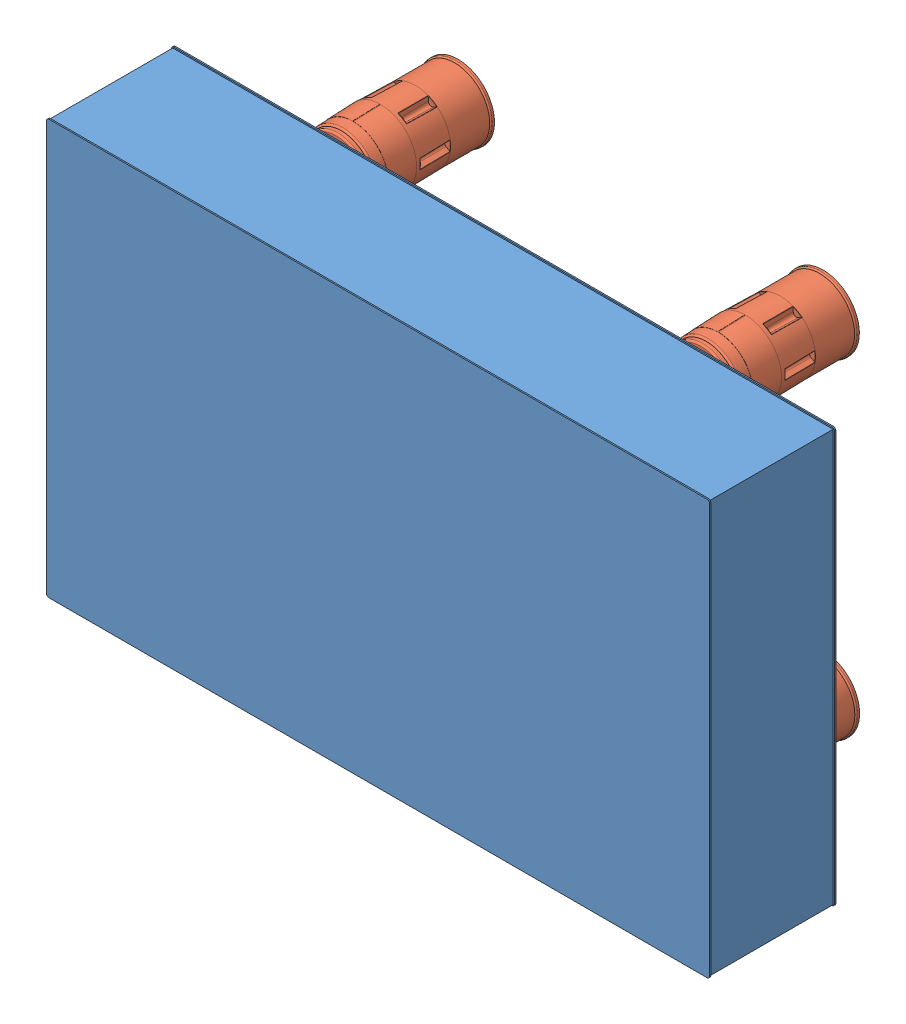
SolidWorks assembly table_with_legs_large, configuration Default. Lengths in mm.
Overall size (2400 1500 950.88).
5 component instances, 2 part files, 12 mates.
Components (placement in the parent):
- M-RS-58-18-1: M-RS-58-18 [Default] at (-679.8721 921.2576 1141.4726) x (1 0 0) z (0 -1 0) size (2400 457 1500)
- S-2000-119.5-2: S-2000-119.5 [-000] at (-19.6071 1517.7497 633.0884) size (263.3 283.03 493.88)
- S-2000-119.5-3: S-2000-119.5 [-000] at (-1340.137 1517.7497 633.0884) size (263.3 283.03 493.88)
- S-2000-119.5-4: S-2000-119.5 [-000] at (-1340.137 324.7654 633.0884) size (263.3 283.03 493.88)
- S-2000-119.5-5: S-2000-119.5 [-000] at (-19.5524 324.568 632.301) size (263.3 283.03 493.88)
Mates (geometry in assembly coordinates):
- Coincident4: coincident anti-aligned: plane of M-RS-58-18-1 through (-1870.2201 180.9096 684.4726) normal (0 0 -1); plane of S-2000-119.5-2 through (-19.6071 1517.7497 684.4726) normal (0 0 1)
- Coincident5: coincident anti-aligned: plane of M-RS-58-18-1 through (-1870.2201 180.9096 684.4726) normal (0 0 -1); plane of S-2000-119.5-3 through (-1340.137 1517.7497 684.4726) normal (0 0 1)
- Coincident6: coincident anti-aligned: plane of M-RS-58-18-1 through (-1870.2201 180.9096 684.4726) normal (0 0 -1); plane of S-2000-119.5-4 through (-1340.137 324.7654 684.4726) normal (0 0 1)
- Distance1: distance = 153 mm: point of S-2000-119.5-4; line of M-RS-58-18-1 through (515.1279 176.2576 689.2726) axis (-1 0 0)
- Distance2: distance = 536 mm: line of M-RS-58-18-1 through (-1874.8721 176.2576 689.2726) axis (0 1 0); point of S-2000-119.5-4
- Distance3: distance = 153 mm: point of S-2000-119.5-3; line of M-RS-58-18-1 through (-1874.8721 1666.2576 689.2726) axis (1 0 0)
- Distance4: distance = 536 mm: line of M-RS-58-18-1 through (-1874.8721 176.2576 689.2726) axis (0 1 0); point of S-2000-119.5-3
- Distance6: distance = 536 mm: point of S-2000-119.5-2; line of M-RS-58-18-1 through (515.1279 1666.2576 689.2726) axis (0 -1 0)
- Distance7: distance = 153 mm: point of S-2000-119.5-2; line of M-RS-58-18-1 through (-1874.8721 1666.2576 689.2726) axis (1 0 0)
- Coincident17: coincident anti-aligned: plane of M-RS-58-18-1 through (-1870.2201 180.9096 684.4726) normal (0 0 -1); plane of S-2000-119.5-5 through (-51.282 276.2989 684.4726) normal (0 0 1)
- Distance10: distance = 153 mm: point of S-2000-119.5-5; line of M-RS-58-18-1 through (515.1279 176.2576 689.2726) axis (-1 0 0)
- Distance11: distance = 536 mm: point of S-2000-119.5-5; line of M-RS-58-18-1 through (515.1279 1666.2576 689.2726) axis (0 -1 0)
